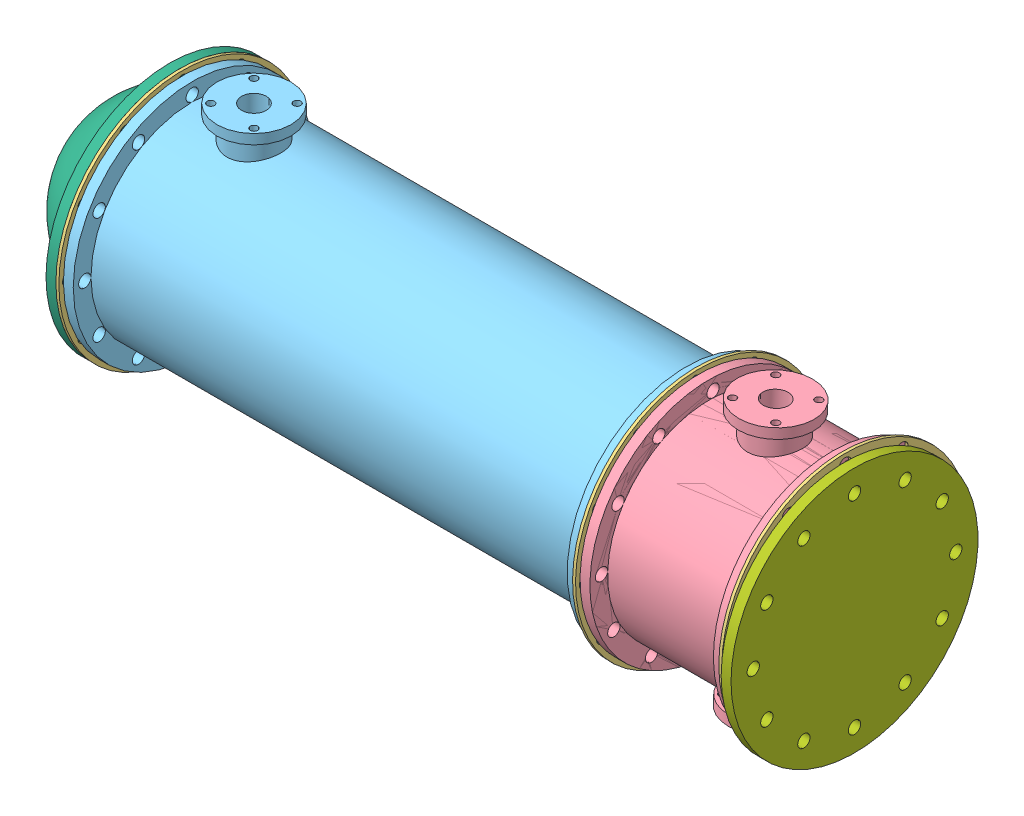
SolidWorks assembly Assem1, configuration Default. Lengths in mm.
Overall size (15580 6758.5 6758.5).
14 component instances, 7 part files, 23 mates.
Components (placement in the parent):
- Tubes-1: Tubes [Default] at (9909.6463 5398.3612 7064.323) size (12100 3600 3600)
- Holder-1: Holder [Default] at (8309.6463 5398.3612 7064.323) size (100 1750 3598.61)
- Holder-7: Holder [Default] at (6809.6463 5398.3612 7064.323) x (1 0 0) z (0 0 -1) size (100 1750 3598.61)
- Holder-8: Holder [Default] at (3809.6463 5398.3612 7064.323) x (1 0 0) z (0 0 -1) size (100 1750 3598.61)
- Holder-9: Holder [Default] at (809.6463 5398.3612 7064.323) x (1 0 0) z (0 0 -1) size (100 1750 3598.61)
- Holder-10: Holder [Default] at (5309.6463 5398.3612 7064.323) size (100 1750 3598.61)
- Holder-11: Holder [Default] at (2309.6463 5398.3612 7064.323) size (100 1750 3598.61)
- Rubber Gasket-1: Rubber Gasket [Default] at (10109.6463 5398.3612 7064.323) x (1 0 0) z (0 0.46794 0.88376) size (60 5000 5000)
- steam channel-1: steam channel [Default] at (10169.6463 5398.3612 7064.323) x (1 0 0) z (0 0.038958 0.999241) size (2900 5300 4817.68)
- Tubes housing-1: Tubes housing [Default] at (-290.3537 5398.3612 7064.323) size (10400 5058.84 4817.68)
- Rubber Gasket-2: Rubber Gasket [Default] at (-350.3537 5398.3612 7064.323) size (60 5000 5000)
- End Cap-1: End Cap [Default] at (-350.3537 5398.3612 7064.323) x (-1 0 0) z (0 0 -1) size (1900 5000 5000)
- Rubber Gasket-3: Rubber Gasket [Default] at (13069.6463 5398.3612 7064.323) size (60 5000 5000)
- Outside Flange-1: Outside Flange [Default] at (13129.6463 5249.1713 7076.0297) size (200 5000 5000)
Mates (geometry in assembly coordinates):
- Concentric1: concentric anti-aligned: cylinder of Tubes-1 through (10109.6463 5548.3612 8564.323) axis (-1 0 0) radius 70; circle of Holder-1
- Concentric2: concentric aligned: cylinder of Tubes-1 through (10109.6463 5548.3612 5564.323) axis (-1 0 0) radius 70; cylinder of Holder-1 through (8409.6463 5548.3612 5564.323) axis (-1 0 0) radius 70
- Concentric5: concentric aligned: circle of Tubes-1; circle of Holder-7
- Coincident3: coincident anti-aligned: cylinder of Tubes-1 through (10109.6463 5248.3612 8564.323) axis (-1 0 0) radius 70; circle of Holder-7
- Distance1: distance = 1500 mm anti-aligned: plane of Tubes-1 through (9909.6463 5398.3612 7064.323) normal (-1 0 0); plane of Holder-1 through (8409.6463 5398.3612 7064.323) normal (1 0 0)
- Distance2: distance = 3000 mm anti-aligned: plane of Holder-7 through (6909.6463 5398.3612 7064.323) normal (1 0 0); plane of Tubes-1 through (9909.6463 5398.3612 7064.323) normal (-1 0 0)
- Distance3: distance = 0 mm anti-aligned: plane of Rubber Gasket-1 through (10109.6463 5398.3612 7064.323) normal (-1 0 0); plane of Tubes-1 through (10109.6463 5398.3612 7064.323) normal (1 0 0)
- Concentric6: concentric anti-aligned: cylinder of Tubes-1 through (10109.6463 5398.3612 7064.323) axis (-1 0 0) radius 1800; circle of Rubber Gasket-1
- Distance5: distance = 0 mm anti-aligned: plane of steam channel-1 through (10169.6463 5398.3612 7064.323) normal (-1 0 0); plane of Rubber Gasket-1 through (10169.6463 5398.3612 7064.323) normal (1 0 0)
- Concentric7: concentric anti-aligned: cylinder of Rubber Gasket-1 through (10109.6463 5398.3612 7064.323) axis (1 0 0) radius 1800; cylinder of steam channel-1 through (10369.6463 5398.3612 7064.323) axis (-1 0 0) radius 1782.5403
- Concentric8: concentric aligned: cylinder of Tubes-1 through (10109.6463 5398.3612 7064.323) axis (-1 0 0) radius 1800; cylinder of Tubes housing-1 through (-90.3537 5398.3612 7064.323) axis (-1 0 0) radius 1782.5403
- Distance6: distance = 0 mm anti-aligned: plane of Tubes housing-1 through (10109.6463 5398.3612 7064.323) normal (1 0 0); plane of Rubber Gasket-1 through (10109.6463 5398.3612 7064.323) normal (-1 0 0)
- Distance7: distance = 60 mm aligned: plane of Rubber Gasket-2 through (-350.3537 5398.3612 7064.323) normal (-1 0 0); plane of Tubes housing-1 through (-290.3537 5398.3612 7064.323) normal (-1 0 0)
- Concentric9: concentric anti-aligned: cylinder of Tubes housing-1 through (-90.3537 5398.3612 7064.323) axis (-1 0 0) radius 1782.5403; cylinder of Rubber Gasket-2 through (-350.3537 5398.3612 7064.323) axis (1 0 0) radius 1800
- Parallel2: parallel aligned: plane of Rubber Gasket-2 through (-350.3537 5398.3612 7064.323) normal (-1 0 0); plane of End Cap-1 through (-550.3537 5398.3612 7064.323) normal (-1 0 0)
- Distance8: distance = 0 mm: plane of End Cap-1 through (-350.3537 5398.3612 7064.323) normal (1 0 0); plane of Rubber Gasket-2 through (-350.3537 5398.3612 7064.323) normal (-1 0 0)
- Distance9: distance = 0 mm: plane of End Cap-1 through (-350.3537 5398.3612 7064.323) normal (1 0 0); plane of Rubber Gasket-2 through (-350.3537 5398.3612 7064.323) normal (-1 0 0)
- Concentric11: concentric: cylinder of Tubes housing-1 through (-90.3537 5398.3612 7064.323) axis (-1 0 0) radius 1782.5403; sphere of End Cap-1
- Distance10: distance = 60 mm aligned: plane of steam channel-1 through (13069.6463 5398.3612 7064.323) normal (1 0 0); plane of Rubber Gasket-3 through (13129.6463 5398.3612 7064.323) normal (1 0 0)
- Concentric12: concentric anti-aligned: cylinder of steam channel-1 through (10369.6463 5398.3612 7064.323) axis (-1 0 0) radius 1782.5403; circle of Rubber Gasket-3
- Parallel4: parallel anti-aligned: plane of steam channel-1 through (10369.6463 5398.3612 7064.323) normal (1 0 0); plane of Outside Flange-1 through (13129.6463 5249.1713 7076.0297) normal (-1 0 0)
- Concentric14: concentric aligned: cylinder of steam channel-1 through (10369.6463 3473.8192 6051.0297) axis (-1 0 0) radius 125; cylinder of Outside Flange-1 through (13329.6463 3473.8192 6051.0297) axis (-1 0 0) radius 125
- Distance12: distance = 0 mm anti-aligned: plane of Outside Flange-1 through (13129.6463 5249.1713 7076.0297) normal (-1 0 0); plane of Rubber Gasket-3 through (13129.6463 5398.3612 7064.323) normal (1 0 0)
